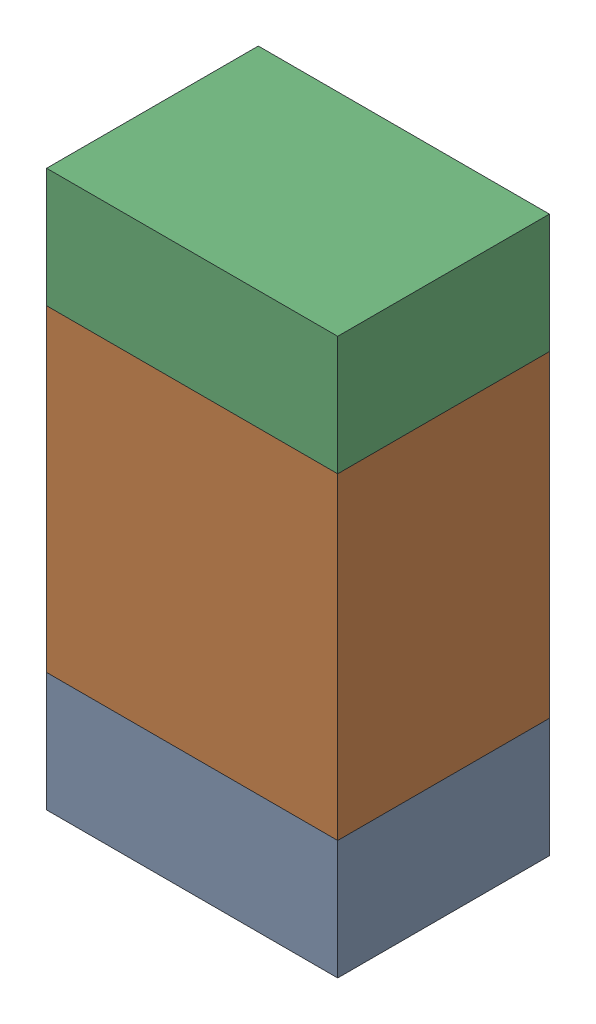
SolidWorks assembly R603_1PCB, configuration Default. Lengths in mm.
Overall size (0.55 1.05 0.4).
6 component instances, 2 part files, 0 mates.
Components (placement in the parent):
- 846483288-1: 846483288 [Default] at (105.0001 109.3876 -2.0638) size (0.55 0.22 0.4)
  - Extruded_12-1: Extruded_12 [Default] at origin size (0.55 0.22 0.4)
- 846483424-1: 846483424 [Default] at (105.0001 109.8001 -2.0638) size (0.55 0.6 0.4)
  - Extruded_13-1: Extruded_13 [Default] at origin size (0.55 0.6 0.4)
- 846483288-2: 846483288 [Default] at (105.0001 110.2126 -2.0638) size (0.55 0.22 0.4)
  - Extruded_12-1: Extruded_12 [Default] at origin size (0.55 0.22 0.4)
